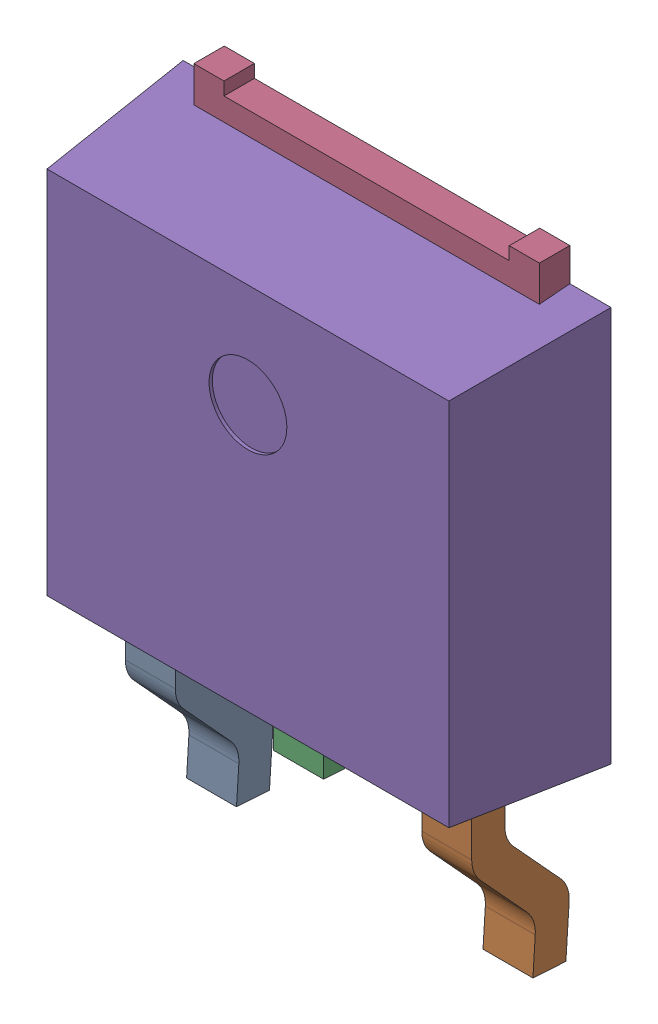
SolidWorks assembly IC22_1.step, configuration Default. Lengths in mm.
Overall size (6.6 9.53 2.3).
3 component instances, 2 part files, 0 mates.
Components (placement in the parent):
- 6348793488_1.step-11: 6348793488_1.step [Default] at (377.958 305.354 0) x (1 0 0) z (0 0 1) size (6.6 9.53 2.3)
  - Linear Pattern 01_1.step-21: Linear Pattern 01_1.step [Default] at origin size (5.34 3.53 1.5)
  - Open CASCADE STEP translator 7.5 5.121.1.2_1.step-21: Open CASCADE STEP translator 7.5 5.121.1.2_1.step [Default] at origin size (6.6 6.61 2.3)
